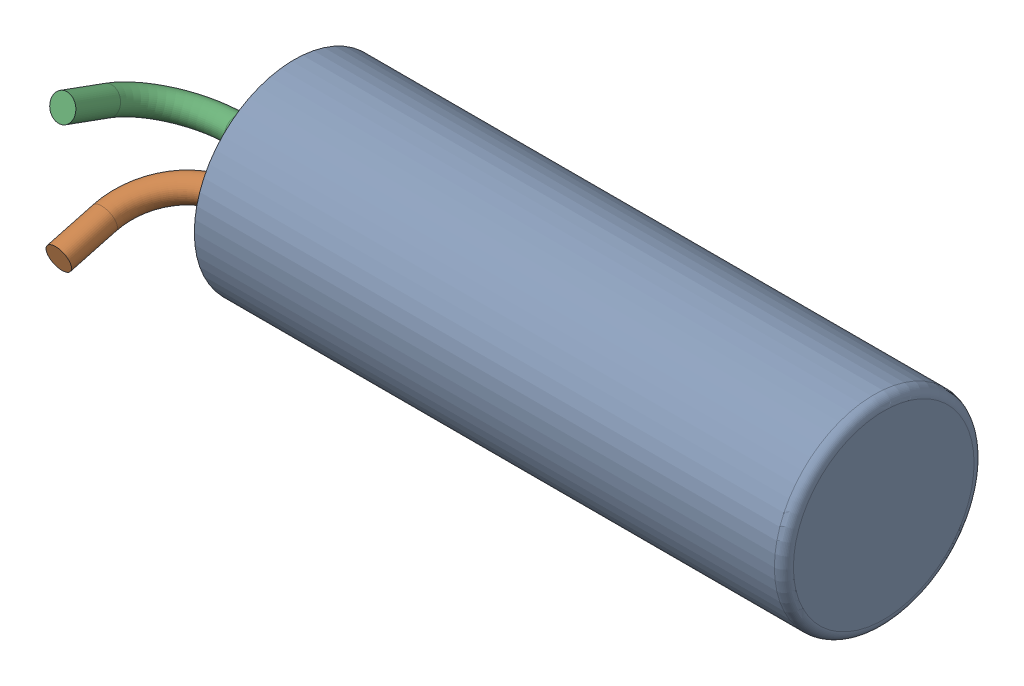
SolidWorks assembly Y1K60, configuration 默认. Lengths in mm.
Overall size (8.19 2.1 8.19).
5 component instances, 2 part files, 0 mates.
Components (placement in the parent):
- XTAL-XYL_SMD-1: XTAL-XYL_SMD [默认] at (-31.2982 10.5185 -1.0912) x (0 -1 0) z (0.656059 0 0.75471) size (2.1 7.22 5.65)
  - XTAL-XYL-1: XTAL-XYL [默认] at (0.0959 -0.4998 -2.6168) x (0 -0.656059 0.75471) z (0 0.75471 0.656059) size (2.1 2.1 6.2)
    - User_Library-R38_100mils_Fillet-1: User_Library-R38_100mils_Fillet [默认] at origin size (2.1 2.1 6.2)
  - 零件1-1: 零件1 [默认] at (0.7193 -1.5563 -0.0297) x (0.965926 0.169801 -0.195333) z (-0.258819 0.633704 -0.728993) size (0.26 1.23 1.33)
  - 零件1-2: 零件1 [默认] at (-0.6339 -1.5286 -0.0615) x (0.939693 -0.224385 0.258126) z (0.34202 0.616494 -0.709195) size (0.26 1.23 1.33)
